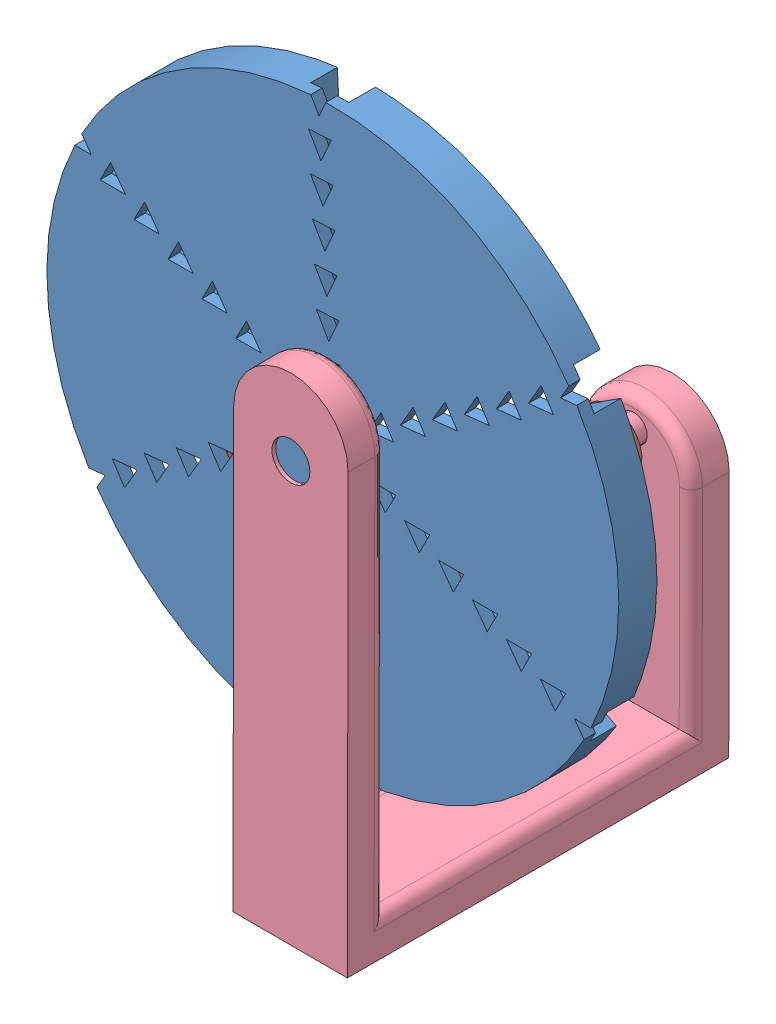
SolidWorks assembly E1_S4_AVA_E, configuration Default. Lengths in mm.
Overall size (201.79 210.93 100).
6 component instances, 4 part files, 11 mates.
Components (placement in the parent):
- E1_S4_AVA_P3-1: E1_S4_AVA_P3 [Default] at (-39.95 133.104 0) x (0.455143 0.890418 0) z (-0.890418 0.455143 0) size (150 20 149.95)
- E1_S4_AVA_P2-1: E1_S4_AVA_P2 [Default] at (-40.0142 95.604 -43) x (0.101232 -0.994863 0) z (0.994863 0.101232 0) size (65.25 70 73.95)
- E1_S4_AVA_P1-1: E1_S4_AVA_P1 [Default] at (-36.218 58.2967 -10) x (-0.090252 -0.995919 0) z (-0.995919 0.090252 0) size (9.5 4 9.5)
- E1_S4_AVA_P1-2: E1_S4_AVA_P1 [Default] at (-9.6032 117.5453 -10) x (0.704893 0.709314 0) z (0.709314 -0.704893 0) size (9.5 4 9.5)
- E1_S4_AVA_P1-3: E1_S4_AVA_P1 [Default] at (-74.2214 110.9701 -10) x (-0.090252 -0.995919 0) z (-0.995919 0.090252 0) size (9.5 4 9.5)
- E1_S4_AVA_P4-2: E1_S4_AVA_P4 [Default] at (-40.0014 103.104 -79) x (0.999999 -0.001712 0) z (0 0 1) size (30 130 100)
Mates (geometry in assembly coordinates):
- Concentric7: concentric: cylinder of E1_S4_AVA_P2-1 through (-74.2214 110.9701 -13) axis (0 0 1) radius 4; cylinder of E1_S4_AVA_P1-3 through (-74.2214 110.9701 -6) axis (0 0 -1) radius 4
- Coincident8: coincident: plane of E1_S4_AVA_P2-1 through (-74.2214 110.9701 -6) normal (0 0 -1); plane of E1_S4_AVA_P1-3 through (-74.2214 110.9701 -6) normal (0 0 1)
- Concentric9: concentric: cylinder of E1_S4_AVA_P2-1 through (-9.6032 117.5453 -13) axis (0 0 1) radius 4; cylinder of E1_S4_AVA_P1-2 through (-9.6032 117.5453 -6) axis (0 0 -1) radius 4
- Coincident10: coincident: plane of E1_S4_AVA_P2-1 through (-9.6032 117.5453 -6) normal (0 0 -1); plane of E1_S4_AVA_P1-2 through (-9.6032 117.5453 -6) normal (0 0 1)
- Concentric10: concentric: cylinder of E1_S4_AVA_P2-1 through (-36.218 58.2967 -13) axis (0 0 1) radius 4; cylinder of E1_S4_AVA_P1-1 through (-36.218 58.2967 -6) axis (0 0 -1) radius 4
- Coincident11: coincident: plane of E1_S4_AVA_P2-1 through (-36.218 58.2967 -6) normal (0 0 -1); plane of E1_S4_AVA_P1-1 through (-36.218 58.2967 -6) normal (0 0 1)
- Parallel3: parallel: plane of E1_S4_AVA_P3-1 through (-39.95 133.104 0) normal (0 0 1); plane of E1_S4_AVA_P2-1 through (-40.0142 95.604 -73) normal (0 0 -1)
- Coincident16: coincident: plane of E1_S4_AVA_P3-1 through (-39.95 133.104 -3) normal (0 0 -1); plane of E1_S4_AVA_P2-1 through (-9.6032 117.5453 -3) normal (0 0 1)
- Concentric13: concentric: cylinder of E1_S4_AVA_P2-1 through (-40.0142 95.604 -58) axis (0 0 -1) radius 3.5; cylinder of E1_S4_AVA_P4-2 through (-40.0142 95.604 -64) axis (0 0 -1) radius 3.5
- Concentric14: concentric: cylinder of E1_S4_AVA_P3-1 through (-39.95 133.104 10) axis (0 0 -1) radius 5; cylinder of E1_S4_AVA_P4-2 through (-39.95 133.104 1) axis (0 0 1) radius 5
- Distance2: distance = 1 mm: plane of E1_S4_AVA_P3-1 through (-39.95 133.104 10) normal (0 0 1); plane of E1_S4_AVA_P4-2 through (-25.1384 23.0785 11) normal (0 0 1)
